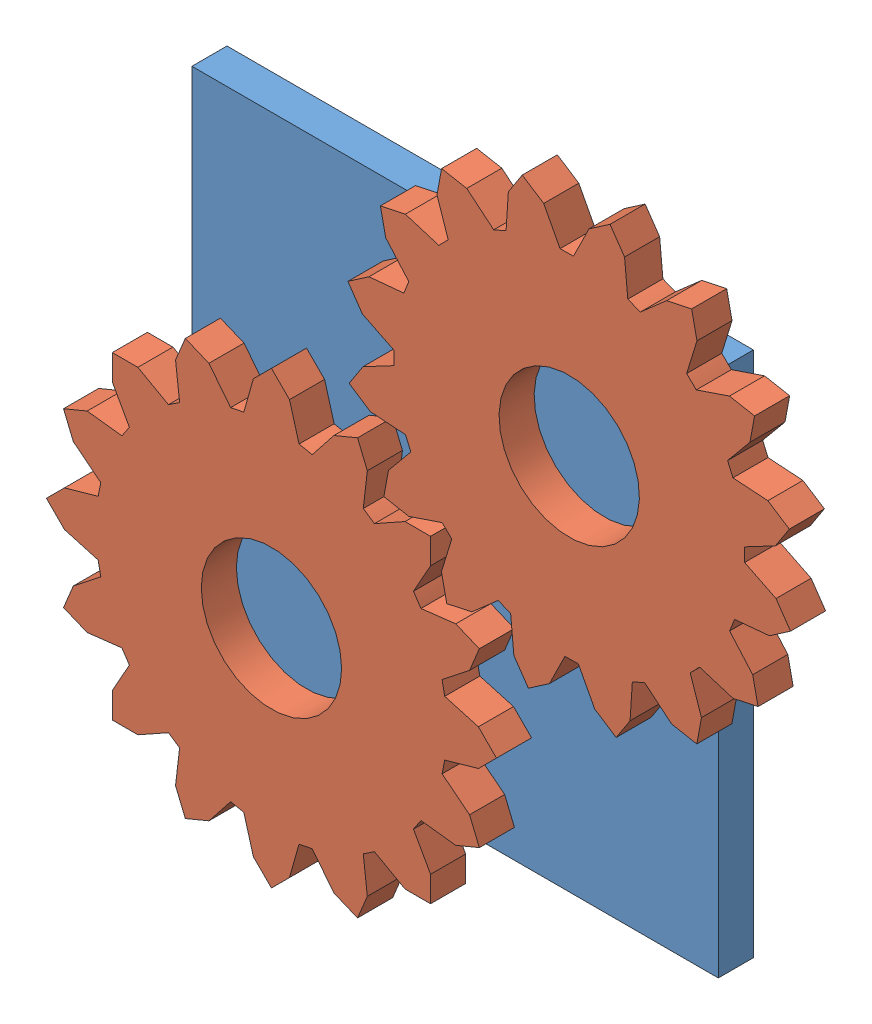
SolidWorks assembly gears_connected_animated, configuration Default. Lengths in mm.
Overall size (238.16 238.16 20).
3 component instances, 2 part files, 5 mates.
Components (placement in the parent):
- plane-2: plane [Default] at origin size (150 150 10)
- gear1-1: gear1 [Default] at (-42.5146 -42.3381 10) size (128.25 128.25 10)
- gear1-2: gear1 [Default] at (42.3381 42.5146 10) x (0.823696 0.567031 0) z (0 0 1) size (128.25 128.25 10)
Mates (geometry in assembly coordinates):
- Coincident1: coincident anti-aligned: plane of plane-2 through (0 0 10) normal (0 0 1); plane of gear1-1 through (-42.5146 -42.3381 10) normal (0 0 -1)
- Coincident2: coincident anti-aligned: plane of plane-2 through (0 0 10) normal (0 0 1); plane of gear1-2 through (42.3381 42.5146 10) normal (0 0 -1)
- Concentric1: concentric anti-aligned: circle of gear1-1
- Concentric2: concentric anti-aligned: circle of gear1-2
- Coincident9: coincident anti-aligned: plane of plane-2 through (0 0 10) normal (0 0 1); plane of gear1-2 through (42.3381 42.5146 10) normal (0 0 -1)
